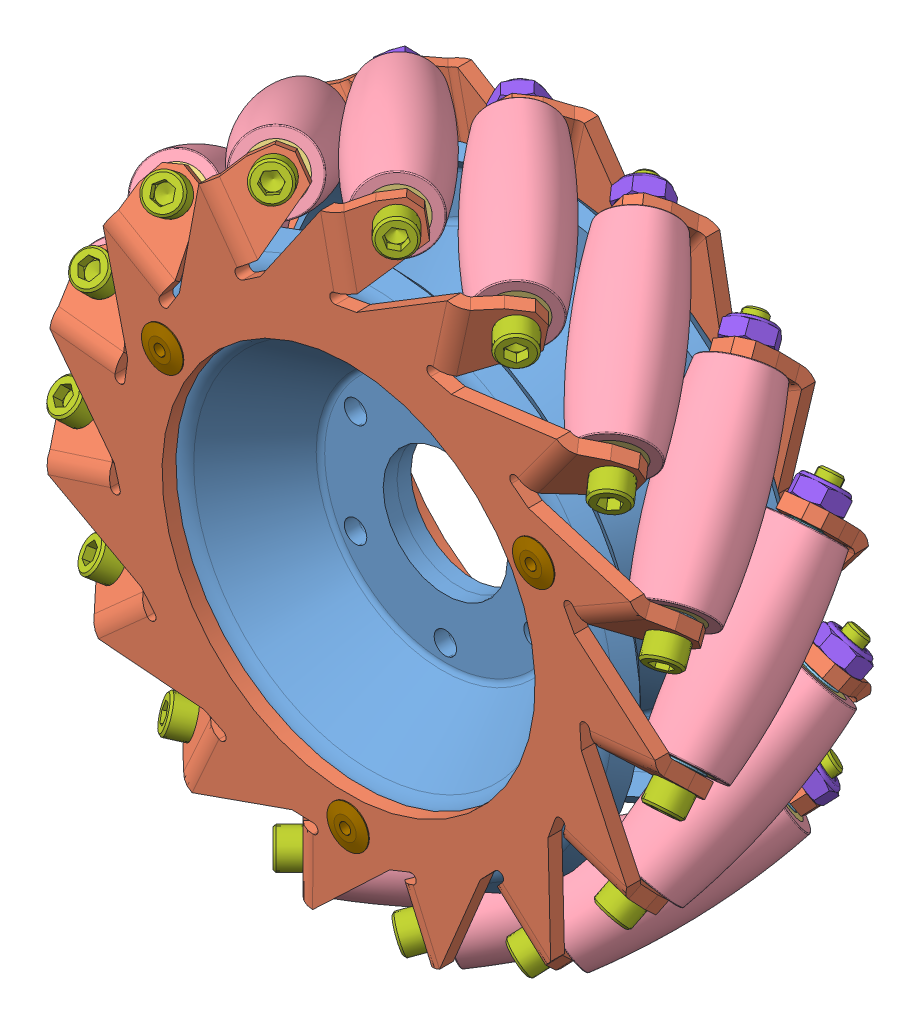
SolidWorks assembly am-3479R+6+SR+Mecanum+Right, configuration Default. Lengths in mm.
Overall size (195.76 195.56 52.39).
130 component instances, 9 part files, 0 mates.
Components (placement in the parent):
- ip-3479_hub-1: ip-3479_hub [Default] x (0 0 1) z (1 0 0) size (22.23 118.71 118.71)
- ip-3479_hub-2: ip-3479_hub [Default] x (0 0 -1) z (-1 0 0) size (22.23 118.71 118.71)
- am-0676a Right Plate HD-1: am-0676a Right Plate HD [Default] at (0 0 25.4) x (0 0 1) z (0.999437 -0.033548 0) size (13.05 146.22 146.64)
- am-0676a Right Plate HD-2: am-0676a Right Plate HD [Default] at (0 0 -25.4) x (0 0 -1) z (-0.899685 -0.43654 0) size (13.05 146.22 146.64)
- am-3479_roller-1: am-3479_roller [Default] at (26.9568 -57.1919 -0.0841) x (-0.024254 0.933673 0.357305) z (0.762892 -0.213694 0.610189) size (19.48 44.35 19.48)
  - am-3698_core PC-1: am-3698_core PC [Default] at (-2.9239 1.0394 0.8367) size (14.92 43.18 14.92)
  - am-3698_skin TPU v2-1: am-3698_skin TPU v2 [Default] at (-2.9239 22.6294 0.8367) x (1 0 0) z (0 1 0) size (19.48 19.48 43.18)
  - am-0603 MBC Bushing MU04TH04-1: am-0603 MBC Bushing MU04TH04 [Default] at (-2.9239 -20.9316 0.8367) x (0 1 0) z (0 0 1) size (6.36 7.94 7.94)
  - am-0603 MBC Bushing MU04TH04-2: am-0603 MBC Bushing MU04TH04 [Default] at (-2.9239 16.6604 0.8367) x (0 1 0) z (-0.707574 0 0.70664) size (6.36 7.94 7.94)
  - am-0701a 6IN SR Roller Axle-1: am-0701a 6IN SR Roller Axle [Default] at (-2.9239 23.2136 0.8367) x (0 -1 0) z (0 0 1) size (44.35 6.35 6.35)
- 10-32x2250_shcs_HX-SHCS 0.19-32x1.375x1-C-1: 10-32x2250_shcs_HX-SHCS 0.19-32x1.375x1-C [Default] at (7.4798 -69.0799 21.4752) x (0.646071 0.287384 -0.707109) z (-0.562057 -0.447661 -0.695479) size (61.98 7.94 7.94)
- 10-32 Nylock Jam Nut_90633A411-1: 10-32 Nylock Jam Nut_90633A411 [Default] at (43.3772 -53.1121 -17.8137) x (0.73445 0.018133 0.678421) z (-0.207789 0.957644 0.199354) size (9.53 4.55 11)
- 10-32 Nylock Jam Nut_90633A411-2: 10-32 Nylock Jam Nut_90633A411 [Default] at (18.0245 -66.1634 -17.8137) x (0.678329 -0.282162 0.678421) z (0.199684 0.959367 0.199354) size (9.53 4.55 11)
- 10-32 Nylock Jam Nut_90633A411-3: 10-32 Nylock Jam Nut_90633A411 [Default] at (-10.4449 -67.7745 -17.8137) x (0.504918 -0.533669 0.678421) z (0.57263 0.795206 0.199354) size (9.53 4.55 11)
- 10-32 Nylock Jam Nut_90633A411-4: 10-32 Nylock Jam Nut_90633A411 [Default] at (-37.1083 -57.6667 -17.8137) x (0.244203 -0.6929 0.678421) z (0.846563 0.493548 0.199354) size (9.53 4.55 11)
- 10-32 Nylock Jam Nut_90633A411-5: 10-32 Nylock Jam Nut_90633A411 [Default] at (-57.3553 -37.5879 -17.8137) x (-0.058737 -0.732322 0.678421) z (0.974118 0.10655 0.199354) size (9.53 4.55 11)
- 10-32 Nylock Jam Nut_90633A411-6: 10-32 Nylock Jam Nut_90633A411 [Default] at (-67.685 -11.0098 -17.8137) x (-0.351521 -0.645119 0.678421) z (0.933239 -0.298871 0.199354) size (9.53 4.55 11)
- 10-32 Nylock Jam Nut_90633A411-7: 10-32 Nylock Jam Nut_90633A411 [Default] at (-66.3114 17.4721 -17.8137) x (-0.583524 -0.446369 0.678421) z (0.730994 -0.652615 0.199354) size (9.53 4.55 11)
- 10-32 Nylock Jam Nut_90633A411-8: 10-32 Nylock Jam Nut_90633A411 [Default] at (-53.472 42.9328 -17.8137) x (-0.71463 -0.170437 0.678421) z (0.402354 -0.893515 0.199354) size (9.53 4.55 11)
- 10-32 Nylock Jam Nut_90633A411-9: 10-32 Nylock Jam Nut_90633A411 [Default] at (-31.3867 60.9701 -17.8137) x (-0.72217 0.134964 0.678421) z (0.004143 -0.979919 0.199354) size (9.53 4.55 11)
- 10-32 Nylock Jam Nut_90633A411-10: 10-32 Nylock Jam Nut_90633A411 [Default] at (-3.8744 68.4651 -17.8137) x (-0.604841 0.417029 0.678421) z (-0.394784 -0.896886 0.199354) size (9.53 4.55 11)
- 10-32 Nylock Jam Nut_90633A411-11: 10-32 Nylock Jam Nut_90633A411 [Default] at (24.3078 64.1218 -17.8137) x (-0.382928 0.626986 0.678421) z (-0.725449 -0.658773 0.199354) size (9.53 4.55 11)
- 10-32 Nylock Jam Nut_90633A411-12: 10-32 Nylock Jam Nut_90633A411 [Default] at (48.287 48.6913 -17.8137) x (-0.094805 0.728531 0.678421) z (-0.930678 -0.306752 0.199354) size (9.53 4.55 11)
- 10-32 Nylock Jam Nut_90633A411-13: 10-32 Nylock Jam Nut_90633A411 [Default] at (63.9169 24.8417 -17.8137) x (0.209712 0.704107 0.678421) z (-0.974984 0.098309 0.199354) size (9.53 4.55 11)
- 10-32 Nylock Jam Nut_90633A411-14: 10-32 Nylock Jam Nut_90633A411 [Default] at (68.495 -3.3033 -17.8137) x (0.477967 0.557936 0.678421) z (-0.850706 0.486371 0.199354) size (9.53 4.55 11)
- 10-32 Nylock Jam Nut_90633A411-15: 10-32 Nylock Jam Nut_90633A411 [Default] at (61.2297 -30.8772 -17.8137) x (0.663578 0.315293 0.678421) z (-0.579334 0.790336 0.199354) size (9.53 4.55 11)
- 10-32x2250_shcs_HX-SHCS 0.19-32x1.375x1-C-2: 10-32x2250_shcs_HX-SHCS 0.19-32x1.375x1-C [Default] at (-21.2642 -66.15 21.4752) x (0.707105 -0.000242 -0.707109) z (-0.695545 -0.18035 -0.695479) size (61.98 7.94 7.94)
- 10-32x2250_shcs_HX-SHCS 0.19-32x1.375x1-C-3: 10-32x2250_shcs_HX-SHCS 0.19-32x1.375x1-C [Default] at (-46.3314 -51.7821 21.4752) x (0.645874 -0.287827 -0.707109) z (-0.708767 0.118146 -0.695479) size (61.98 7.94 7.94)
- 10-32x2250_shcs_HX-SHCS 0.19-32x1.375x1-C-4: 10-32x2250_shcs_HX-SHCS 0.19-32x1.375x1-C [Default] at (-63.3875 -28.4606 21.4752) x (0.472965 -0.525643 -0.707109) z (-0.599436 0.396213 -0.695479) size (61.98 7.94 7.94)
- 10-32x2250_shcs_HX-SHCS 0.19-32x1.375x1-C-5: 10-32x2250_shcs_HX-SHCS 0.19-32x1.375x1-C [Default] at (-69.4833 -0.218 21.4752) x (0.218277 -0.672571 -0.707109) z (-0.386458 0.605772 -0.695479) size (61.98 7.94 7.94)
- 10-32x2250_shcs_HX-SHCS 0.19-32x1.375x1-C-6: 10-32x2250_shcs_HX-SHCS 0.19-32x1.375x1-C [Default] at (-63.5649 28.0623 21.4752) x (-0.074153 -0.703206 -0.707109) z (-0.106657 0.710587 -0.695479) size (61.98 7.94 7.94)
- 10-32x2250_shcs_HX-SHCS 0.19-32x1.375x1-C-7: 10-32x2250_shcs_HX-SHCS 0.19-32x1.375x1-C [Default] at (-46.6554 51.4903 21.4752) x (-0.353762 -0.612249 -0.707109) z (0.191585 0.692535 -0.695479) size (61.98 7.94 7.94)
- 10-32x2250_shcs_HX-SHCS 0.19-32x1.375x1-C-8: 10-32x2250_shcs_HX-SHCS 0.19-32x1.375x1-C [Default] at (-21.6789 66.0152 21.4752) x (-0.572202 -0.41543 -0.707109) z (0.456701 0.554737 -0.695479) size (61.98 7.94 7.94)
- 10-32x2250_shcs_HX-SHCS 0.19-32x1.375x1-C-9: 10-32x2250_shcs_HX-SHCS 0.19-32x1.375x1-C [Default] at (7.0462 69.1255 21.4752) x (-0.691703 -0.146778 -0.707109) z (0.642849 0.321021 -0.695479) size (61.98 7.94 7.94)
- 10-32x2250_shcs_HX-SHCS 0.19-32x1.375x1-C-10: 10-32x2250_shcs_HX-SHCS 0.19-32x1.375x1-C [Default] at (34.5529 60.2833 21.4752) x (-0.691602 0.147252 -0.707109) z (0.717843 0.031797 -0.695479) size (61.98 7.94 7.94)
- 10-32x2250_shcs_HX-SHCS 0.19-32x1.375x1-C-11: 10-32x2250_shcs_HX-SHCS 0.19-32x1.375x1-C [Default] at (56.0851 41.0176 21.4752) x (-0.571917 0.415821 -0.707109) z (0.668715 -0.262925 -0.695479) size (61.98 7.94 7.94)
- 10-32x2250_shcs_HX-SHCS 0.19-32x1.375x1-C-12: 10-32x2250_shcs_HX-SHCS 0.19-32x1.375x1-C [Default] at (67.9196 14.6596 21.4752) x (-0.353343 0.612492 -0.707109) z (0.50396 -0.512185 -0.695479) size (61.98 7.94 7.94)
- 10-32x2250_shcs_HX-SHCS 0.19-32x1.375x1-C-13: 10-32x2250_shcs_HX-SHCS 0.19-32x1.375x1-C [Default] at (68.0103 -14.2332 21.4752) x (-0.073672 0.703256 -0.707109) z (0.252066 -0.672883 -0.695479) size (61.98 7.94 7.94)
- 10-32x2250_shcs_HX-SHCS 0.19-32x1.375x1-C-14: 10-32x2250_shcs_HX-SHCS 0.19-32x1.375x1-C [Default] at (56.3413 -40.6649 21.4752) x (0.218738 0.672422 -0.707109) z (-0.043412 -0.717234 -0.695479) size (61.98 7.94 7.94)
- 10-32x2250_shcs_HX-SHCS 0.19-32x1.375x1-C-15: 10-32x2250_shcs_HX-SHCS 0.19-32x1.375x1-C [Default] at (34.9305 -60.0654 21.4752) x (0.473325 0.525319 -0.707109) z (-0.331385 -0.637568 -0.695479) size (61.98 7.94 7.94)
- am-3479_roller-2: am-3479_roller [Default] at (1.3642 -63.2118 -0.0841) x (0.357602 0.862818 0.357305) z (0.61002 -0.505515 0.610189) size (19.48 44.35 19.48)
  - am-3698_core PC-1: am-3698_core PC [Default] at (-2.9239 1.0394 0.8367) size (14.92 43.18 14.92)
  - am-3698_skin TPU v2-1: am-3698_skin TPU v2 [Default] at (-2.9239 22.6294 0.8367) x (1 0 0) z (0 1 0) size (19.48 19.48 43.18)
  - am-0603 MBC Bushing MU04TH04-1: am-0603 MBC Bushing MU04TH04 [Default] at (-2.9239 -20.9316 0.8367) x (0 1 0) z (0 0 1) size (6.36 7.94 7.94)
  - am-0603 MBC Bushing MU04TH04-2: am-0603 MBC Bushing MU04TH04 [Default] at (-2.9239 16.6604 0.8367) x (0 1 0) z (-0.707574 0 0.70664) size (6.36 7.94 7.94)
  - am-0701a 6IN SR Roller Axle-1: am-0701a 6IN SR Roller Axle [Default] at (-2.9239 23.2136 0.8367) x (0 -1 0) z (0 0 1) size (44.35 6.35 6.35)
- am-3479_roller-3: am-3479_roller [Default] at (-24.4642 -58.3017 -0.0841) x (0.677625 0.642773 0.357305) z (0.351669 -0.709929 0.610189) size (19.48 44.35 19.48)
  - am-3698_core PC-1: am-3698_core PC [Default] at (-2.9239 1.0394 0.8367) size (14.92 43.18 14.92)
  - am-3698_skin TPU v2-1: am-3698_skin TPU v2 [Default] at (-2.9239 22.6294 0.8367) x (1 0 0) z (0 1 0) size (19.48 19.48 43.18)
  - am-0603 MBC Bushing MU04TH04-1: am-0603 MBC Bushing MU04TH04 [Default] at (-2.9239 -20.9316 0.8367) x (0 1 0) z (0 0 1) size (6.36 7.94 7.94)
  - am-0603 MBC Bushing MU04TH04-2: am-0603 MBC Bushing MU04TH04 [Default] at (-2.9239 16.6604 0.8367) x (0 1 0) z (-0.707574 0 0.70664) size (6.36 7.94 7.94)
  - am-0701a 6IN SR Roller Axle-1: am-0701a 6IN SR Roller Axle [Default] at (-2.9239 23.2136 0.8367) x (0 -1 0) z (0 0 1) size (44.35 6.35 6.35)
- am-3479_roller-4: am-3479_roller [Default] at (-46.0626 -43.3107 -0.0841) x (0.880481 0.311587 0.357305) z (0.032512 -0.791589 0.610189) size (19.48 44.35 19.48)
  - am-3698_core PC-1: am-3698_core PC [Default] at (-2.9239 1.0394 0.8367) size (14.92 43.18 14.92)
  - am-3698_skin TPU v2-1: am-3698_skin TPU v2 [Default] at (-2.9239 22.6294 0.8367) x (1 0 0) z (0 1 0) size (19.48 19.48 43.18)
  - am-0603 MBC Bushing MU04TH04-1: am-0603 MBC Bushing MU04TH04 [Default] at (-2.9239 -20.9316 0.8367) x (0 1 0) z (0 0 1) size (6.36 7.94 7.94)
  - am-0603 MBC Bushing MU04TH04-2: am-0603 MBC Bushing MU04TH04 [Default] at (-2.9239 16.6604 0.8367) x (0 1 0) z (-0.707574 0 0.70664) size (6.36 7.94 7.94)
  - am-0701a 6IN SR Roller Axle-1: am-0701a 6IN SR Roller Axle [Default] at (-2.9239 23.2136 0.8367) x (0 -1 0) z (0 0 1) size (44.35 6.35 6.35)
- am-3479_roller-5: am-3479_roller [Default] at (-59.6964 -20.831 -0.0841) x (0.931093 -0.073475 0.357305) z (-0.292267 -0.736376 0.610189) size (19.48 44.35 19.48)
  - am-3698_core PC-1: am-3698_core PC [Default] at (-2.9239 1.0394 0.8367) size (14.92 43.18 14.92)
  - am-3698_skin TPU v2-1: am-3698_skin TPU v2 [Default] at (-2.9239 22.6294 0.8367) x (1 0 0) z (0 1 0) size (19.48 19.48 43.18)
  - am-0603 MBC Bushing MU04TH04-1: am-0603 MBC Bushing MU04TH04 [Default] at (-2.9239 -20.9316 0.8367) x (0 1 0) z (0 0 1) size (6.36 7.94 7.94)
  - am-0603 MBC Bushing MU04TH04-2: am-0603 MBC Bushing MU04TH04 [Default] at (-2.9239 16.6604 0.8367) x (0 1 0) z (-0.707574 0 0.70664) size (6.36 7.94 7.94)
  - am-0701a 6IN SR Roller Axle-1: am-0701a 6IN SR Roller Axle [Default] at (-2.9239 23.2136 0.8367) x (0 -1 0) z (0 0 1) size (44.35 6.35 6.35)
- am-3479_roller-6: am-3479_roller [Default] at (-63.0081 5.2507 -0.0841) x (0.820711 -0.445832 0.357305) z (-0.566511 -0.553837 0.610189) size (19.48 44.35 19.48)
  - am-3698_core PC-1: am-3698_core PC [Default] at (-2.9239 1.0394 0.8367) size (14.92 43.18 14.92)
  - am-3698_skin TPU v2-1: am-3698_skin TPU v2 [Default] at (-2.9239 22.6294 0.8367) x (1 0 0) z (0 1 0) size (19.48 19.48 43.18)
  - am-0603 MBC Bushing MU04TH04-1: am-0603 MBC Bushing MU04TH04 [Default] at (-2.9239 -20.9316 0.8367) x (0 1 0) z (0 0 1) size (6.36 7.94 7.94)
  - am-0603 MBC Bushing MU04TH04-2: am-0603 MBC Bushing MU04TH04 [Default] at (-2.9239 16.6604 0.8367) x (0 1 0) z (-0.707574 0 0.70664) size (6.36 7.94 7.94)
  - am-0701a 6IN SR Roller Axle-1: am-0701a 6IN SR Roller Axle [Default] at (-2.9239 23.2136 0.8367) x (0 -1 0) z (0 0 1) size (44.35 6.35 6.35)
- am-3479_roller-7: am-3479_roller [Default] at (-55.4251 30.4244 -0.0841) x (0.568421 -0.741101 0.357305) z (-0.742799 -0.275535 0.610189) size (19.48 44.35 19.48)
  - am-3698_core PC-1: am-3698_core PC [Default] at (-2.9239 1.0394 0.8367) size (14.92 43.18 14.92)
  - am-3698_skin TPU v2-1: am-3698_skin TPU v2 [Default] at (-2.9239 22.6294 0.8367) x (1 0 0) z (0 1 0) size (19.48 19.48 43.18)
  - am-0603 MBC Bushing MU04TH04-1: am-0603 MBC Bushing MU04TH04 [Default] at (-2.9239 -20.9316 0.8367) x (0 1 0) z (0 0 1) size (6.36 7.94 7.94)
  - am-0603 MBC Bushing MU04TH04-2: am-0603 MBC Bushing MU04TH04 [Default] at (-2.9239 16.6604 0.8367) x (0 1 0) z (-0.707574 0 0.70664) size (6.36 7.94 7.94)
  - am-0701a 6IN SR Roller Axle-1: am-0701a 6IN SR Roller Axle [Default] at (-2.9239 23.2136 0.8367) x (0 -1 0) z (0 0 1) size (44.35 6.35 6.35)
- am-3479_roller-8: am-3479_roller [Default] at (-38.2586 50.3375 -0.0841) x (0.217845 -0.908227 0.357305) z (-0.790651 0.05041 0.610189) size (19.48 44.35 19.48)
  - am-3698_core PC-1: am-3698_core PC [Default] at (-2.9239 1.0394 0.8367) size (14.92 43.18 14.92)
  - am-3698_skin TPU v2-1: am-3698_skin TPU v2 [Default] at (-2.9239 22.6294 0.8367) x (1 0 0) z (0 1 0) size (19.48 19.48 43.18)
  - am-0603 MBC Bushing MU04TH04-1: am-0603 MBC Bushing MU04TH04 [Default] at (-2.9239 -20.9316 0.8367) x (0 1 0) z (0 0 1) size (6.36 7.94 7.94)
  - am-0603 MBC Bushing MU04TH04-2: am-0603 MBC Bushing MU04TH04 [Default] at (-2.9239 16.6604 0.8367) x (0 1 0) z (-0.707574 0 0.70664) size (6.36 7.94 7.94)
  - am-0701a 6IN SR Roller Axle-1: am-0701a 6IN SR Roller Axle [Default] at (-2.9239 23.2136 0.8367) x (0 -1 0) z (0 0 1) size (44.35 6.35 6.35)
- am-3479_roller-9: am-3479_roller [Default] at (-14.4769 61.5468 -0.0841) x (-0.170398 -0.918313 0.357305) z (-0.701792 0.367638 0.610189) size (19.48 44.35 19.48)
  - am-3698_core PC-1: am-3698_core PC [Default] at (-2.9239 1.0394 0.8367) size (14.92 43.18 14.92)
  - am-3698_skin TPU v2-1: am-3698_skin TPU v2 [Default] at (-2.9239 22.6294 0.8367) x (1 0 0) z (0 1 0) size (19.48 19.48 43.18)
  - am-0603 MBC Bushing MU04TH04-1: am-0603 MBC Bushing MU04TH04 [Default] at (-2.9239 -20.9316 0.8367) x (0 1 0) z (0 0 1) size (6.36 7.94 7.94)
  - am-0603 MBC Bushing MU04TH04-2: am-0603 MBC Bushing MU04TH04 [Default] at (-2.9239 16.6604 0.8367) x (0 1 0) z (-0.707574 0 0.70664) size (6.36 7.94 7.94)
  - am-0701a 6IN SR Roller Axle-1: am-0701a 6IN SR Roller Axle [Default] at (-2.9239 23.2136 0.8367) x (0 -1 0) z (0 0 1) size (44.35 6.35 6.35)
- am-3479_roller-10: am-3479_roller [Default] at (11.808 62.1141 -0.0841) x (-0.529178 -0.769613 0.357305) z (-0.491587 0.621299 0.610189) size (19.48 44.35 19.48)
  - am-3698_core PC-1: am-3698_core PC [Default] at (-2.9239 1.0394 0.8367) size (14.92 43.18 14.92)
  - am-3698_skin TPU v2-1: am-3698_skin TPU v2 [Default] at (-2.9239 22.6294 0.8367) x (1 0 0) z (0 1 0) size (19.48 19.48 43.18)
  - am-0603 MBC Bushing MU04TH04-1: am-0603 MBC Bushing MU04TH04 [Default] at (-2.9239 -20.9316 0.8367) x (0 1 0) z (0 0 1) size (6.36 7.94 7.94)
  - am-0603 MBC Bushing MU04TH04-2: am-0603 MBC Bushing MU04TH04 [Default] at (-2.9239 16.6604 0.8367) x (0 1 0) z (-0.707574 0 0.70664) size (6.36 7.94 7.94)
  - am-0701a 6IN SR Roller Axle-1: am-0701a 6IN SR Roller Axle [Default] at (-2.9239 23.2136 0.8367) x (0 -1 0) z (0 0 1) size (44.35 6.35 6.35)
- am-3479_roller-11: am-3479_roller [Default] at (36.0512 51.9413 -0.0841) x (-0.796458 -0.487841 0.357305) z (-0.196382 0.767531 0.610189) size (19.48 44.35 19.48)
  - am-3698_core PC-1: am-3698_core PC [Default] at (-2.9239 1.0394 0.8367) size (14.92 43.18 14.92)
  - am-3698_skin TPU v2-1: am-3698_skin TPU v2 [Default] at (-2.9239 22.6294 0.8367) x (1 0 0) z (0 1 0) size (19.48 19.48 43.18)
  - am-0603 MBC Bushing MU04TH04-1: am-0603 MBC Bushing MU04TH04 [Default] at (-2.9239 -20.9316 0.8367) x (0 1 0) z (0 0 1) size (6.36 7.94 7.94)
  - am-0603 MBC Bushing MU04TH04-2: am-0603 MBC Bushing MU04TH04 [Default] at (-2.9239 16.6604 0.8367) x (0 1 0) z (-0.707574 0 0.70664) size (6.36 7.94 7.94)
  - am-0701a 6IN SR Roller Axle-1: am-0701a 6IN SR Roller Axle [Default] at (-2.9239 23.2136 0.8367) x (0 -1 0) z (0 0 1) size (44.35 6.35 6.35)
- am-3479_roller-12: am-3479_roller [Default] at (54.0609 32.7873 -0.0841) x (-0.926023 -0.121716 0.357305) z (0.132779 0.78105 0.610189) size (19.48 44.35 19.48)
  - am-3698_core PC-1: am-3698_core PC [Default] at (-2.9239 1.0394 0.8367) size (14.92 43.18 14.92)
  - am-3698_skin TPU v2-1: am-3698_skin TPU v2 [Default] at (-2.9239 22.6294 0.8367) x (1 0 0) z (0 1 0) size (19.48 19.48 43.18)
  - am-0603 MBC Bushing MU04TH04-1: am-0603 MBC Bushing MU04TH04 [Default] at (-2.9239 -20.9316 0.8367) x (0 1 0) z (0 0 1) size (6.36 7.94 7.94)
  - am-0603 MBC Bushing MU04TH04-2: am-0603 MBC Bushing MU04TH04 [Default] at (-2.9239 16.6604 0.8367) x (0 1 0) z (-0.707574 0 0.70664) size (6.36 7.94 7.94)
  - am-0701a 6IN SR Roller Axle-1: am-0701a 6IN SR Roller Axle [Default] at (-2.9239 23.2136 0.8367) x (0 -1 0) z (0 0 1) size (44.35 6.35 6.35)
- am-3479_roller-13: am-3479_roller [Default] at (62.7229 7.9642 -0.0841) x (-0.895471 0.265454 0.357305) z (0.438982 0.659519 0.610189) size (19.48 44.35 19.48)
  - am-3698_core PC-1: am-3698_core PC [Default] at (-2.9239 1.0394 0.8367) size (14.92 43.18 14.92)
  - am-3698_skin TPU v2-1: am-3698_skin TPU v2 [Default] at (-2.9239 22.6294 0.8367) x (1 0 0) z (0 1 0) size (19.48 19.48 43.18)
  - am-0603 MBC Bushing MU04TH04-1: am-0603 MBC Bushing MU04TH04 [Default] at (-2.9239 -20.9316 0.8367) x (0 1 0) z (0 0 1) size (6.36 7.94 7.94)
  - am-0603 MBC Bushing MU04TH04-2: am-0603 MBC Bushing MU04TH04 [Default] at (-2.9239 16.6604 0.8367) x (0 1 0) z (-0.707574 0 0.70664) size (6.36 7.94 7.94)
  - am-0701a 6IN SR Roller Axle-1: am-0701a 6IN SR Roller Axle [Default] at (-2.9239 23.2136 0.8367) x (0 -1 0) z (0 0 1) size (44.35 6.35 6.35)
- am-3479_roller-14: am-3479_roller [Default] at (60.5395 -18.236 -0.0841) x (-0.710083 0.606725 0.357305) z (0.66928 0.42395 0.610189) size (19.48 44.35 19.48)
  - am-3698_core PC-1: am-3698_core PC [Default] at (-2.9239 1.0394 0.8367) size (14.92 43.18 14.92)
  - am-3698_skin TPU v2-1: am-3698_skin TPU v2 [Default] at (-2.9239 22.6294 0.8367) x (1 0 0) z (0 1 0) size (19.48 19.48 43.18)
  - am-0603 MBC Bushing MU04TH04-1: am-0603 MBC Bushing MU04TH04 [Default] at (-2.9239 -20.9316 0.8367) x (0 1 0) z (0 0 1) size (6.36 7.94 7.94)
  - am-0603 MBC Bushing MU04TH04-2: am-0603 MBC Bushing MU04TH04 [Default] at (-2.9239 16.6604 0.8367) x (0 1 0) z (-0.707574 0 0.70664) size (6.36 7.94 7.94)
  - am-0701a 6IN SR Roller Axle-1: am-0701a 6IN SR Roller Axle [Default] at (-2.9239 23.2136 0.8367) x (0 -1 0) z (0 0 1) size (44.35 6.35 6.35)
- am-3479_roller-15: am-3479_roller [Default] at (47.8883 -41.2831 -0.0841) x (-0.401916 0.843088 0.357305) z (0.783854 0.115077 0.610189) size (19.48 44.35 19.48)
  - am-3698_core PC-1: am-3698_core PC [Default] at (-2.9239 1.0394 0.8367) size (14.92 43.18 14.92)
  - am-3698_skin TPU v2-1: am-3698_skin TPU v2 [Default] at (-2.9239 22.6294 0.8367) x (1 0 0) z (0 1 0) size (19.48 19.48 43.18)
  - am-0603 MBC Bushing MU04TH04-1: am-0603 MBC Bushing MU04TH04 [Default] at (-2.9239 -20.9316 0.8367) x (0 1 0) z (0 0 1) size (6.36 7.94 7.94)
  - am-0603 MBC Bushing MU04TH04-2: am-0603 MBC Bushing MU04TH04 [Default] at (-2.9239 16.6604 0.8367) x (0 1 0) z (-0.707574 0 0.70664) size (6.36 7.94 7.94)
  - am-0701a 6IN SR Roller Axle-1: am-0701a 6IN SR Roller Axle [Default] at (-2.9239 23.2136 0.8367) x (0 -1 0) z (0 0 1) size (44.35 6.35 6.35)
- am-1226 steel rivet 1875 125-250 grip-1: am-1226 steel rivet 1875 125-250 grip [Default] at (19.9857 -44.9716 -15.0813) x (0.985757 0.168176 0) z (-0.168176 0.985757 0) size (9.53 11.11 9.53)
- am-1226 steel rivet 1875 125-250 grip-2: am-1226 steel rivet 1875 125-250 grip [Default] at (-42.6193 24.6062 -15.0813) x (-0.99171 0.128499 0) z (-0.128499 -0.99171 0) size (9.53 11.11 9.53)
- am-1226 steel rivet 1875 125-250 grip-3: am-1226 steel rivet 1875 125-250 grip [Default] at (28.9536 39.7939 -15.0813) x (0.892255 0.451532 0) z (-0.451532 0.892255 0) size (9.53 11.11 9.53)
- am-1226 steel rivet 1875 125-250 grip-4: am-1226 steel rivet 1875 125-250 grip [Default] at (42.6193 24.6063 15.0812) x (0.934139 0.35691 0) z (0.35691 -0.934139 0) size (9.53 11.11 9.53)
- am-1226 steel rivet 1875 125-250 grip-5: am-1226 steel rivet 1875 125-250 grip [Default] at (-42.6193 24.6062 15.0812) x (-0.689528 -0.724259 0) z (-0.724259 0.689528 0) size (9.53 11.11 9.53)
- am-1226 steel rivet 1875 125-250 grip-6: am-1226 steel rivet 1875 125-250 grip [Default] at (0 -49.2125 15.0812) x (-0.060828 0.998148 0) z (0.998148 0.060828 0) size (9.53 11.11 9.53)
